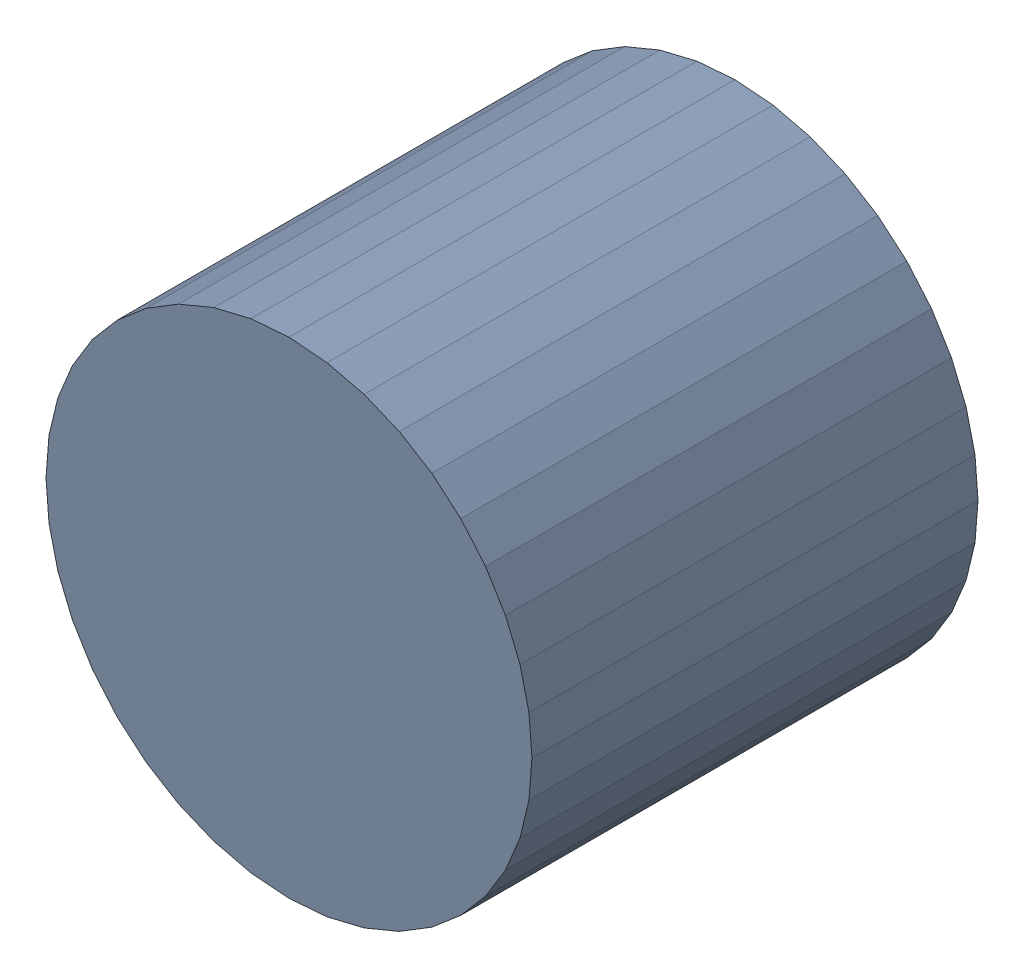
SolidWorks assembly C10_Motor_3Kanaloa_v2.0.0_Motor, configuration Default. Lengths in mm.
Overall size (6.32 6.32 5.8).
2 component instances, 1 part files, 0 mates.
Components (placement in the parent):
- 352892112-1: 352892112 [Default] at (46.423 72.39 0) size (6.32 6.32 5.8)
  - Extruded_11-1: Extruded_11 [Default] at origin size (6.32 6.32 5.8)
